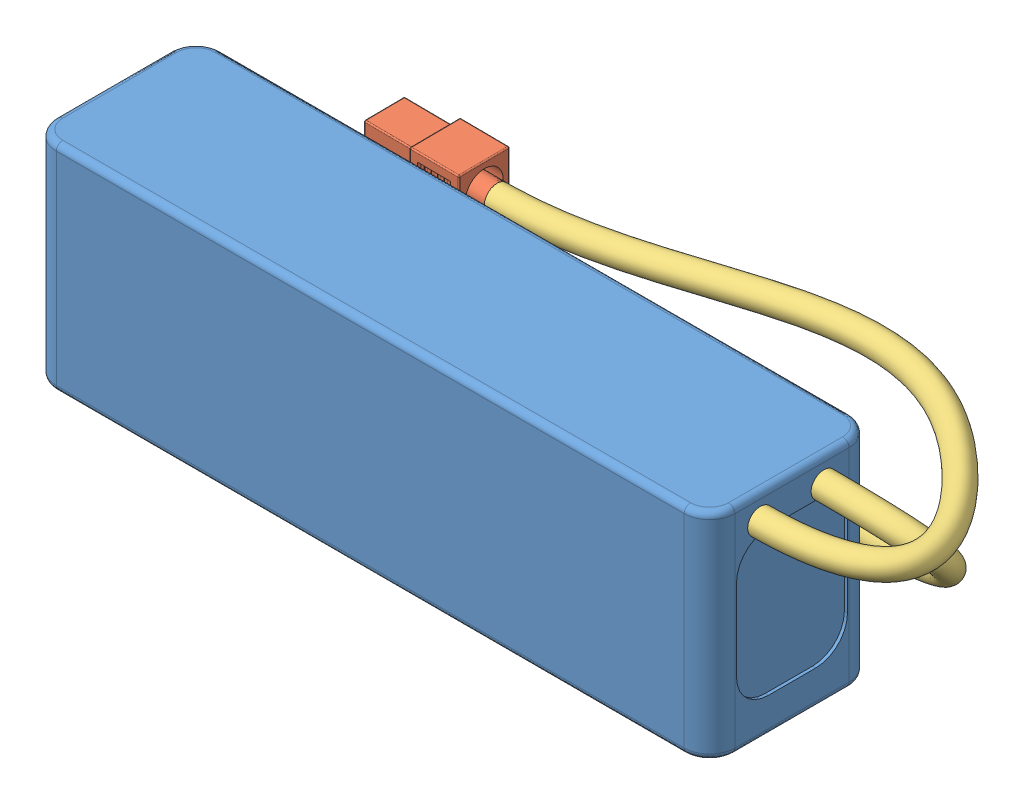
SolidWorks assembly Assembly_Multistar_Battery_3000mah, configuration Default. Lengths in mm.
Overall size (126.94 34 42.99).
3 component instances, 3 part files, 18 mates.
Components (placement in the parent):
- Multistar_3000mAh_4S_Lipo_Battery-1: Multistar_3000mAh_4S_Lipo_Battery [Default] at origin size (107 34 26)
- XT60 Buchse-1: XT60 Buchse [Default] at (1.6219 3.7602 -20.8554) x (0.008726 0.999924 0.008725) z (-0.999962 0.008727 -0.000152) size (15.68 8.11 21.83)
- Part3^Assembly_Multistar_Battery_3000mah-1: Part3^Assembly_Multistar_Battery_3000mah [Default] at (68.5 0 0) x (0 0 -1) z (1 0 0) size (36.99 24.06 86.25) (virtual)
Mates (geometry in assembly coordinates):
- Coincident1: coincident aligned: plane of Multistar_3000mAh_4S_Lipo_Battery-1 through (0 0 0) normal (0 0 1); plane of assembly through (0 0 0) normal (0 0 1)
- Coincident2: coincident aligned: plane of Multistar_3000mAh_4S_Lipo_Battery-1 through (0 0 0) normal (0 1 0); plane of assembly through (0 0 0) normal (0 1 0)
- Coincident3: coincident aligned: plane of Multistar_3000mAh_4S_Lipo_Battery-1 through (0 0 0) normal (1 0 0); plane of assembly through (0 0 0) normal (1 0 0)
- InPlace1: in place: plane of Multistar_3000mAh_4S_Lipo_Battery-1 through (-78.5 -7.5 -3.875) normal (-1 0 0); plane of ? through (-78.5 0 0) normal (-1 0 0); moOrthogonalPlaneRef_w of Multistar_3000mAh_4S_Lipo_Battery-1 through (-78.5 -7.5 -3.875) normal (-1 0 0); line of ? through (-55 -78.5 0) axis (0 0 1); plane of Multistar_3000mAh_4S_Lipo_Battery-1 through (-78.5 -7.5 -3.875) normal (-1 0 0); plane of ? through (-78.5 0 0) normal (0 0 1); plane of Multistar_3000mAh_4S_Lipo_Battery-1 through (-78.5 -7.5 -3.875) normal (-1 0 0); unknown of ?
- Coincident4: coincident aligned: plane of Multistar_3000mAh_4S_Lipo_Battery-1; plane of ?
- Coincident5: coincident aligned: moOrthogonalPlaneRef_w of Multistar_3000mAh_4S_Lipo_Battery-1 through (-78.5 0 0) normal (0 1 0); plane of ?
- Coincident6: coincident anti-aligned: moOrthogonalPlaneRef_w of Multistar_3000mAh_4S_Lipo_Battery-1 through (-78.5 0 0) normal (0 0 -1); plane of ? through (-78.5 0 0) normal (0 0 1)
- InPlace2: in place: plane of Multistar_3000mAh_4S_Lipo_Battery-1 through (68.5 -9.2 1.25) normal (1 0 0); plane of Part3^Assembly_Multistar_Battery_3000mah-1 through (68.5 0 0) normal (1 0 0); plane of Multistar_3000mAh_4S_Lipo_Battery-1 through (68.5 -9.2 1.25) normal (1 0 0); line of Part3^Assembly_Multistar_Battery_3000mah-1 through (-55 68.5 0) axis (0 0 1); plane of Multistar_3000mAh_4S_Lipo_Battery-1 through (68.5 -9.2 1.25) normal (1 0 0); plane of Part3^Assembly_Multistar_Battery_3000mah-1 through (68.5 0 0) normal (0 0 -1); plane of Multistar_3000mAh_4S_Lipo_Battery-1 through (68.5 -11.4423 1.75) normal (1 0 0); unknown of Part3^Assembly_Multistar_Battery_3000mah-1
- Coincident7: coincident aligned: plane of Multistar_3000mAh_4S_Lipo_Battery-1; plane of ?
- Coincident8: coincident aligned: moOrthogonalPlaneRef_w of Multistar_3000mAh_4S_Lipo_Battery-1 through (68.5 0 0) normal (0 1 0); plane of Part3^Assembly_Multistar_Battery_3000mah-1
- Coincident9: coincident anti-aligned: moOrthogonalPlaneRef_w of Multistar_3000mAh_4S_Lipo_Battery-1 through (68.5 0 0) normal (0 0 1); plane of Part3^Assembly_Multistar_Battery_3000mah-1 through (68.5 0 0) normal (0 0 -1)
- InPlace3: in place: plane of Multistar_3000mAh_4S_Lipo_Battery-1 through (68.5 -11.4423 1.75) normal (1 0 0); plane of Part3^Assembly_Multistar_Battery_3000mah-1 through (68.5 0 0) normal (1 0 0); plane of Multistar_3000mAh_4S_Lipo_Battery-1 through (68.5 -11.4423 1.75) normal (1 0 0); line of Part3^Assembly_Multistar_Battery_3000mah-1 through (-55 68.5 0) axis (0 0 1); plane of Multistar_3000mAh_4S_Lipo_Battery-1 through (68.5 -11.4423 1.75) normal (1 0 0); plane of Part3^Assembly_Multistar_Battery_3000mah-1 through (68.5 0 0) normal (0 0 -1); plane of Multistar_3000mAh_4S_Lipo_Battery-1 through (68.5 -11.4423 1.75) normal (1 0 0); unknown of Part3^Assembly_Multistar_Battery_3000mah-1
- Coincident4: coincident aligned: plane of Multistar_3000mAh_4S_Lipo_Battery-1; plane of Part3^Assembly_Multistar_Battery_3000mah-1
- Coincident5: coincident aligned: moOrthogonalPlaneRef_w of Multistar_3000mAh_4S_Lipo_Battery-1 through (68.5 0 0) normal (0 1 0); plane of Part3^Assembly_Multistar_Battery_3000mah-1
- Coincident6: coincident anti-aligned: moOrthogonalPlaneRef_w of Multistar_3000mAh_4S_Lipo_Battery-1 through (68.5 0 0) normal (0 0 1); plane of Part3^Assembly_Multistar_Battery_3000mah-1 through (68.5 0 0) normal (0 0 -1)
- Coincident4: coincident: plane of XT60 Buchse-1 through (-6.1174 10.7999 -17.5956) normal (0.008726 0.999924 0.008725); plane of ? through (-29.1151 11.0564 -23.9989) normal (-0.008726 -0.999924 -0.008725)
- Coincident5: coincident: plane of XT60 Buchse-1 through (-6.116 10.8557 -23.9954) normal (0.000228 0.008724 -0.999962); plane of ? through (-29.2154 -0.4443 -24.0992) normal (-0.000228 -0.008724 0.999962)
- Distance1: distance = 15 mm anti-aligned: plane of ? through (-29.1713 4.6739 -20.8545) normal (0.999962 -0.008727 0.000152); plane of XT60 Buchse-1 through (-14.1726 4.4501 -20.853) normal (-0.999962 0.008727 -0.000152)
